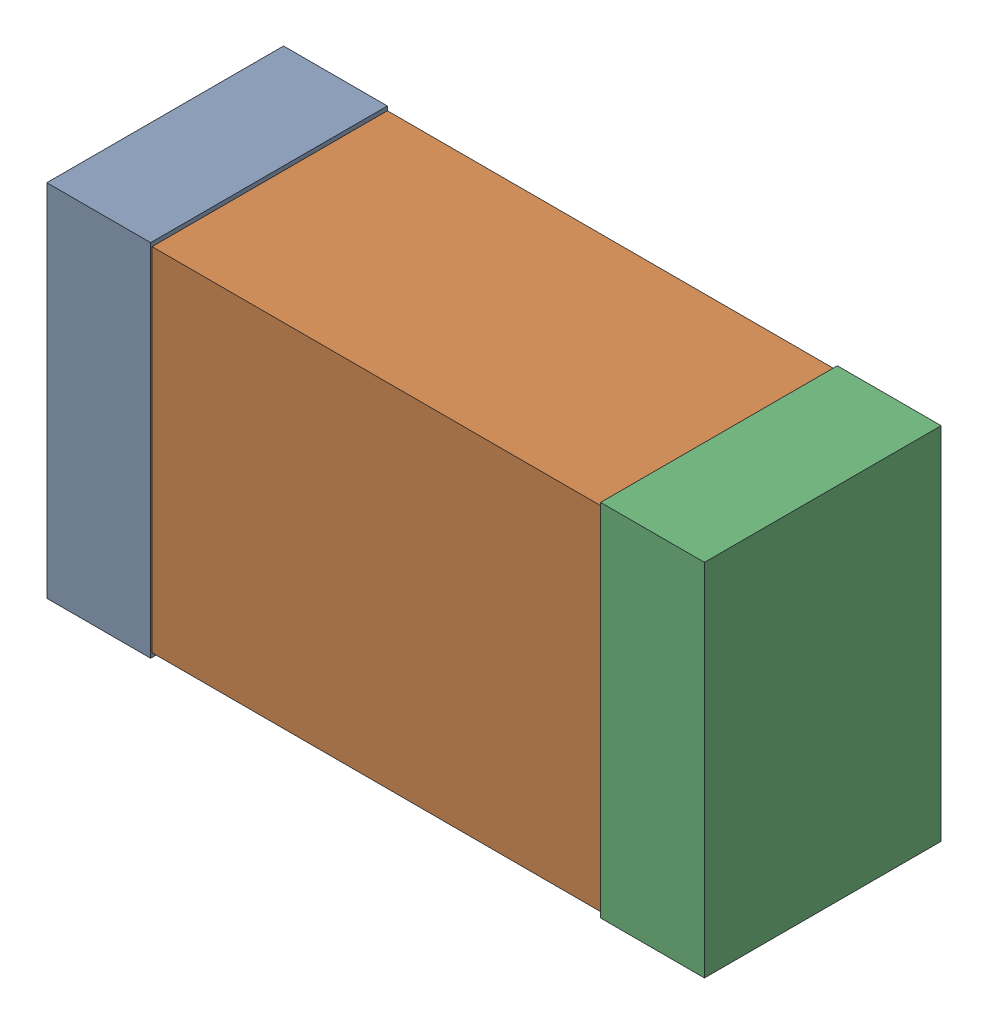
SolidWorks assembly C13_Motor_4Kanaloa_v2.0.0_Motor, configuration Default. Lengths in mm.
Overall size (2.38 1.3 0.85).
6 component instances, 2 part files, 0 mates.
Components (placement in the parent):
- 352877648-1: 352877648 [Default] at (102.437 87.63 0) size (0.38 1.3 0.85)
  - Extruded_14-1: Extruded_14 [Default] at origin size (0.38 1.3 0.85)
- 352877392-1: 352877392 [Default] at (103.437 87.63 0) size (2.2 1.27 0.85)
  - Extruded_15-1: Extruded_15 [Default] at origin size (2.2 1.27 0.85)
- 352877648-2: 352877648 [Default] at (104.437 87.63 0) size (0.38 1.3 0.85)
  - Extruded_14-1: Extruded_14 [Default] at origin size (0.38 1.3 0.85)
